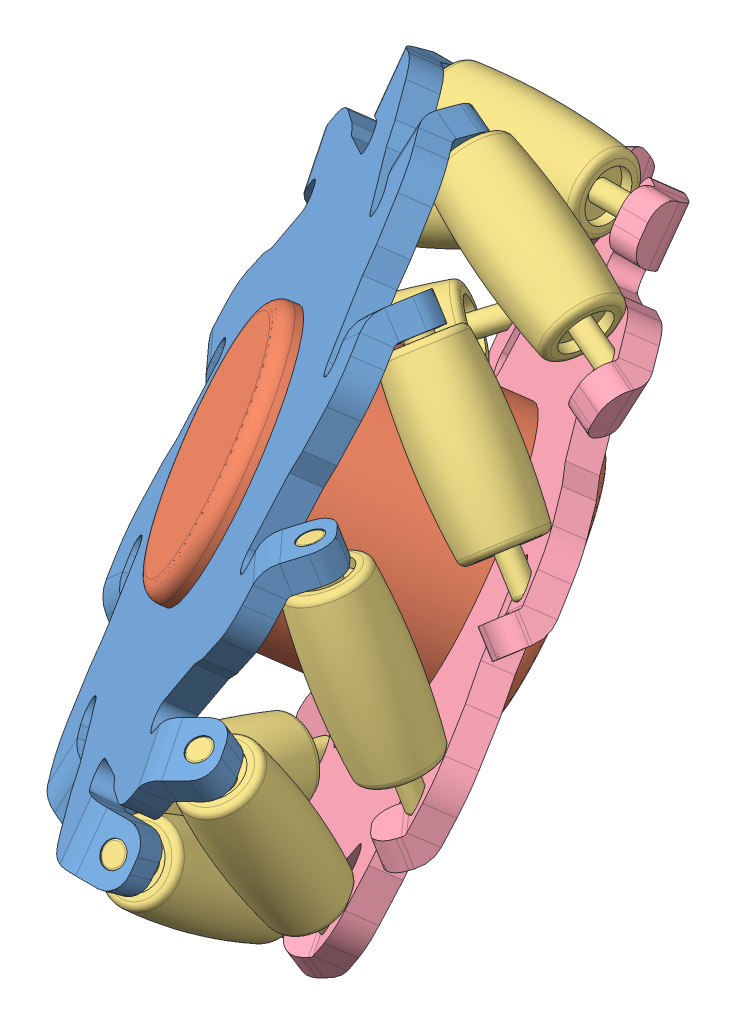
SolidWorks assembly Assem2, configuration Default. Lengths in mm.
Overall size (110.15 111.26 114.6).
13 component instances, 4 part files, 6 mates.
Components (placement in the parent):
- 22-2: 22 [Default] at (56.0668 49.3834 58.4949) x (-0.218508 -0.897857 0.38224) z (0.707107 -0.415627 -0.572061) size (96.82 92.49 8.73)
- 2222-1: 2222 [Default] at (56.0668 49.3834 58.4949) x (-0.567853 0.14831 -0.809659) z (0.707107 -0.415627 -0.572061) size (36 36 49)
- 222-5: 222 [Default] at (61.9099 77.2825 25.4401) size (34 12 12)
- 22222-3: 22222 [Default] at (72.41 39.7771 45.273) x (-0.567853 0.14831 -0.809659) z (-0.707107 0.415627 0.572061) size (95.75 91.46 7.41)
- 222-15: 222 [Default] at (79.796 82.8195 43.5256) x (0.904508 -0.392378 0.167045) z (-0.321554 -0.370218 0.871517) size (34 12 12)
- 222-16: 222 [Default] at (91.7096 73.7679 64.828) x (0.654508 -0.747138 0.115776) z (-0.674793 -0.508208 0.535144) size (34 12 12)
- 222-17: 222 [Default] at (93.1002 53.5853 81.2104) x (0.345492 -0.928773 -0.134224) z (-0.924793 -0.361261 0.119364) size (34 12 12)
- 222-18: 222 [Default] at (83.4366 29.9806 86.4153) x (0.095492 -0.867906 -0.487463) z (-0.976062 0.014492 -0.217008) size (34 12 12)
- 222-19: 222 [Default] at (66.41 11.9702 78.4547) x (0 -0.587785 -0.809017) z (-0.809017 0.475528 -0.345492) size (34 12 12)
- 222-20: 222 [Default] at (48.5239 6.4332 60.3691) x (0.095492 -0.195407 -0.976062) z (-0.487463 0.845746 -0.217008) size (34 12 12)
- 222-21: 222 [Default] at (36.6103 15.4848 39.0667) x (0.345492 0.159352 -0.924793) z (-0.134224 0.983736 0.119364) size (34 12 12)
- 222-22: 222 [Default] at (35.2197 35.6674 22.6843) x (0.654508 0.340988 -0.674793) z (0.115776 0.836789 0.535144) size (34 12 12)
- 222-23: 222 [Default] at (44.8833 59.272 17.4794) x (0.904508 0.280121 -0.321554) z (0.167045 0.461036 0.871517) size (34 12 12)
Mates (geometry in assembly coordinates):
- Coincident3: coincident anti-aligned: plane of 22-2 through (29.8026 38.3302 34.0612) normal (0.707107 -0.415627 -0.572061); plane of 2222-1 through (56.0668 49.3834 58.4949) normal (-0.707107 0.415627 0.572061)
- Concentric27: concentric anti-aligned: circle of 22-2; circle of 2222-1
- Coincident25: coincident aligned: plane of 22-2 through (45.4099 34.0851 28.2183) normal (-1 0 0); plane of 222-5 through (45.4099 77.2825 25.4401) normal (-1 0 0)
- Concentric38: concentric anti-aligned: circle of 2222-1; circle of 22222-3
- Concentric39: concentric aligned: circle of 22-2; circle of 222-5
- Tangent6: tangent: circle of 222-5; plane of 22222-3 through (53.4393 7.7287 45.1085) normal (-0.707107 0.415627 0.572061)
